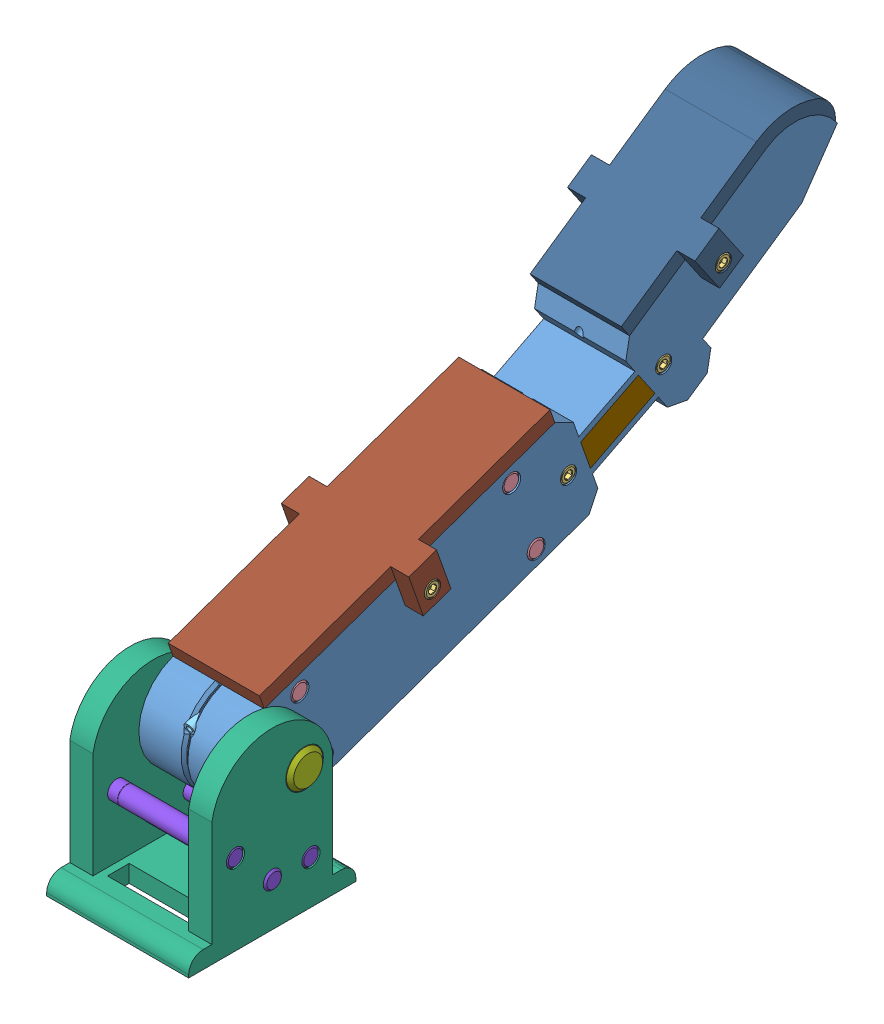
SolidWorks assembly Model B Assembly, configuration Default. Lengths in mm.
Overall size (26.04 78.97 124.79).
25 component instances, 12 part files, 57 mates.
Components (placement in the parent):
- Finger Model B-1: Finger Model B [Default] at (-12.064 21.67 -16.256) x (1 0 0) z (0 -0.332894 0.942964) size (16 27.73 116.61)
- 91253A106-1: 91253A106 [91253A106] at (-12.064 33.526 -38.064) x (1 0.000004 -0.000013) z (0 0.942964 0.332894) size (6.48 6.48 6.63)
- SetScrew-1: SetScrew [90778A103] at (-5.6515 38.9776 -66.5955) x (0 0 -1) z (1 0 0) size (3.29 2.88 3.42)
- Dowel Pins-1: Dowel Pins [97395A445] at (-12.0079 29.664 -19.4945) size (15.88 3.17 3.17)
- Dowel Pins-2: Dowel Pins [97395A445] at (-12.065 42.7701 -56.619) size (15.88 3.17 3.17)
- Dowel Pins-3: Dowel Pins [97395A445] at (-11.938 17.4809 -23.7955) size (15.88 3.17 3.17)
- Dowel Pins-4: Dowel Pins [97395A445] at (-11.938 30.587 -60.92) size (15.88 3.17 3.17)
- 91253A106-2: 91253A106 [91253A106] at (-12.064 60.3378 -94.3511) x (1 -0.000019 0.000027) z (0 0.824674 0.565608) size (6.48 6.48 6.63)
- SetScrew-2: SetScrew [90778A103] at (-5.6515 47.4511 -83.2656) x (0 0 -1) z (1 0 0) size (3.29 2.88 3.42)
- SetScrew-3: SetScrew [90778A103] at (-18.4765 47.4511 -83.2656) x (0 -0.948624 0.316407) z (-1 0 0) size (3.29 2.88 3.42)
- SetScrew-4: SetScrew [90778A103] at (-18.4765 38.9776 -66.5955) x (0 -0.948624 0.316407) z (-1 0 0) size (3.29 2.88 3.42)
- Inlet Tube-1: Inlet Tube [Default] at (-12.064 28.1843 -15.3031) x (1 -0.000168 -0.000059) z (0 -0.332894 0.942964) size (1.8 1.8 7.62)
- New Base Design-2: New Base Design [Default] at (-24.892 21.67 -16.5955) x (0 0 -1) z (1 0 0) size (29.32 30.61 24.89)
- 1-4 inch 1 inch length-1: 1-4 inch 1 inch length [97395A491] at (-12.065 21.67 -16.256) x (1 0 0) z (0 -0.936761 0.34997) size (25.4 6.35 6.35)
- 1-8 inch 1 inch length-1: 1-8 inch 1 inch length [97395A452] at (-12.7 14.1232 -4.1495) x (1 0 0) z (0 0.67783 0.735218) size (25.4 3.17 3.17)
- 1-8 inch 1 inch length-2: 1-8 inch 1 inch length [97395A452] at (-12.7 7.62 -17.382) size (25.4 3.17 3.17)
- Flexure Joint-1: Flexure Joint [Default] at (0 1.8263 0.8872) x (1 0 0) z (0 0.891446 0.453128) size (16 25.4 5.08)
- 2nd Digit Pad^Model B Assembly-1: 2nd Digit Pad^Model B Assembly [Default] at origin (virtual)
- 2nd Digit Pad-1: 2nd Digit Pad [Default] at (-20.066 54.7918 -77.2834) x (0 -0.824674 -0.565608) z (1 0 0) size (11.43 39.04 22.35)
- SetScrew-5: SetScrew [90778A103] at (-2.4765 60.8142 -90.555) x (0 -0.30344 -0.952851) z (1 0 0) size (3.29 2.88 3.42)
- SetScrew-6: SetScrew [90778A103] at (-21.6535 60.8142 -90.555) x (0 -0.948624 0.316407) z (-1 0 0) size (3.29 2.88 3.42)
- 1st Digit Pad-1: 1st Digit Pad [Default] at (-4.064 30.1566 -13.26) x (1 0 0) z (0 0.942964 0.332894) size (22.35 54.01 7.62)
- SetScrew-7: SetScrew [90778A103] at (-2.4765 36.7515 -39.5709) x (0 -0.624397 0.781107) z (1 0 0) size (3.29 2.88 3.42)
- SetScrew-8: SetScrew [90778A103] at (-21.6515 36.7515 -39.5709) x (0 -0.908534 -0.417811) z (-1 0 0) size (3.29 2.88 3.42)
- 1-8 inch 1 inch length-3: 1-8 inch 1 inch length [97395A452] at (-12.3825 7.62 -10.596) size (25.4 3.17 3.17)
Mates (geometry in assembly coordinates):
- Concentric2: concentric anti-aligned: circle of Finger Model B-1; circle of 91253A106-1
- Coincident2: coincident aligned: plane of Finger Model B-1 through (-12.064 25.3664 -14.9511) normal (0 0.942964 0.332894); plane of 91253A106-1 through (-12.064 33.0524 -36.7228) normal (0 0.942964 0.332894)
- Concentric3: concentric anti-aligned: circle of Finger Model B-1; circle of SetScrew-1
- Coincident3: coincident aligned: plane of Finger Model B-1 through (-4.064 21.67 -16.256) normal (1 0 0); plane of SetScrew-1 through (-4.064 38.9776 -66.5955) normal (1 0 0)
- Concentric4: concentric aligned: circle of Finger Model B-1; circle of Dowel Pins-1
- Distance1: distance = 0.0064 mm aligned: plane of Dowel Pins-1 through (-4.0704 29.664 -19.4945) normal (1 0 0); plane of Finger Model B-1 through (-4.064 21.67 -16.256) normal (1 0 0)
- Concentric5: concentric aligned: circle of Finger Model B-1; circle of Dowel Pins-2
- Distance2: distance = 0.0635 mm aligned: plane of Dowel Pins-2 through (-4.1275 42.7701 -56.619) normal (1 0 0); plane of Finger Model B-1 through (-4.064 21.67 -16.256) normal (1 0 0)
- Concentric6: concentric aligned: circle of Finger Model B-1; circle of Dowel Pins-3
- Distance3: distance = 0.0635 mm aligned: plane of Dowel Pins-3 through (-4.0005 17.4809 -23.7955) normal (1 0 0); plane of Finger Model B-1 through (-4.064 21.67 -16.256) normal (1 0 0)
- Concentric7: concentric aligned: circle of Finger Model B-1; circle of Dowel Pins-4
- Distance4: distance = 0.0635 mm aligned: plane of Dowel Pins-4 through (-4.0005 30.587 -60.92) normal (1 0 0); plane of Finger Model B-1 through (-4.064 21.67 -16.256) normal (1 0 0)
- Concentric8: concentric anti-aligned: circle of Finger Model B-1; circle of 91253A106-2
- Coincident8: coincident aligned: plane of Finger Model B-1 through (-12.064 11.5406 -23.2033) normal (0 0.824674 0.565608); plane of 91253A106-2 through (-12.064 59.5333 -93.1781) normal (0 0.824674 0.565608)
- Concentric9: concentric anti-aligned: circle of Finger Model B-1; circle of SetScrew-2
- Coincident9: coincident aligned: plane of Finger Model B-1 through (-4.064 21.67 -16.256) normal (1 0 0); plane of SetScrew-2 through (-4.064 47.4511 -83.2656) normal (1 0 0)
- Concentric10: concentric anti-aligned: circle of Finger Model B-1; circle of SetScrew-3
- Coincident10: coincident aligned: plane of Finger Model B-1 through (-20.064 21.67 -16.256) normal (-1 0 0); plane of SetScrew-3 through (-20.064 47.4511 -83.2656) normal (-1 0 0)
- Concentric11: concentric anti-aligned: circle of Finger Model B-1; circle of SetScrew-4
- Coincident11: coincident aligned: plane of Finger Model B-1 through (-20.064 21.67 -16.256) normal (-1 0 0); plane of SetScrew-4 through (-20.064 38.9776 -66.5955) normal (-1 0 0)
- Coincident12: coincident anti-aligned: circle of Finger Model B-1; circle of Inlet Tube-1
- Coincident13: coincident aligned: plane of Finger Model B-1 through (-5.334 25.7892 -16.1486) normal (0 0.332894 -0.942964); plane of Inlet Tube-1 through (-12.064 28.1843 -15.3031) normal (0 0.332894 -0.942964)
- Concentric17: concentric aligned: circle of Finger Model B-1; circle of New Base Design-2
- Coincident19: coincident anti-aligned: plane of Finger Model B-1 through (-4.064 21.67 -16.256) normal (1 0 0); plane of New Base Design-2 through (-4.064 3.048 -21.844) normal (-1 0 0)
- Concentric21: concentric aligned: circle of New Base Design-2; circle of 1-8 inch 1 inch length-2
- Coincident22: coincident aligned: plane of New Base Design-2 through (0 19.8765 -10.596) normal (1 0 0); plane of 1-8 inch 1 inch length-2 through (0 7.62 -17.382) normal (1 0 0)
- Parallel2: parallel anti-aligned: plane of New Base Design-2 through (0 0 -25.256) normal (0 -1 0); plane of assembly through (0 0 0) normal (0 1 0)
- Coincident24: coincident anti-aligned: plane of New Base Design-2 through (0 0 -25.256) normal (0 -1 0); plane of assembly through (0 0 0) normal (0 1 0)
- Coincident25: coincident aligned: plane of New Base Design-2 through (0 3.048 0) normal (0 0 1); plane of assembly through (0 0 0) normal (0 0 1)
- Coincident26: coincident aligned: plane of New Base Design-2 through (0 19.8765 -10.596) normal (1 0 0); plane of assembly through (0 0 0) normal (1 0 0)
- Concentric22: concentric aligned: circle of New Base Design-2; circle of 1-8 inch 1 inch length-1
- Coincident27: coincident aligned: plane of New Base Design-2 through (0 19.8765 -10.596) normal (1 0 0); plane of 1-8 inch 1 inch length-1 through (0 14.1232 -4.1495) normal (1 0 0)
- Coincident31: coincident anti-aligned: plane of Finger Model B-1 through (-47.2257 35.1954 -64.7601) normal (0 0.891446 0.453128); plane of Flexure Joint-1 through (0 1.8263 0.8872) normal (0 -0.891446 -0.453128)
- Coincident32: coincident aligned: plane of Finger Model B-1 through (-4.064 21.67 -16.256) normal (1 0 0); plane of Flexure Joint-1 through (-4.064 42.6083 -68.1328) normal (1 0 0)
- Coincident33: coincident aligned: plane of Finger Model B-1 through (-20.064 21.67 -16.256) normal (-1 0 0); plane of Flexure Joint-1 through (-20.064 48.3489 -79.4264) normal (-1 0 0)
- Coincident37: coincident anti-aligned: plane of Finger Model B-1 through (-47.2257 39.7239 -62.4582) normal (0 0.453128 -0.891446); plane of Flexure Joint-1 through (-17.524 39.7239 -62.4582) normal (0 -0.453128 0.891446)
- Concentric23: concentric anti-aligned: circle of 2nd Digit Pad-1; circle of SetScrew-5
- Coincident41: coincident aligned: plane of 2nd Digit Pad-1 through (-0.889 54.7918 -77.2834) normal (1 0 0); plane of SetScrew-5 through (-0.889 60.8142 -90.555) normal (1 0 0)
- Concentric24: concentric aligned: circle of 2nd Digit Pad-1; circle of SetScrew-6
- Coincident42: coincident aligned: plane of 2nd Digit Pad-1 through (-23.241 54.7918 -77.2834) normal (-1 0 0); plane of SetScrew-6 through (-23.241 60.8142 -90.555) normal (-1 0 0)
- Parallel3: parallel anti-aligned: plane of Finger Model B-1 through (-4.064 48.9823 -66.5858) normal (0 0.942964 0.332894); plane of 1st Digit Pad-1 through (-4.064 30.1566 -13.26) normal (0 -0.942964 -0.332894)
- Coincident45: coincident anti-aligned: line of Finger Model B-1 through (-4.064 30.1566 -13.26) axis (-1 0 0); line of 1st Digit Pad-1 through (-20.064 30.1566 -13.26) axis (1 0 0)
- Parallel4: parallel aligned: plane of Finger Model B-1 through (-4.064 48.9823 -66.5858) normal (0 0.942964 0.332894); plane of 1st Digit Pad-1 through (-4.064 32.5518 -12.4144) normal (0 0.942964 0.332894)
- Coincident47: coincident aligned: plane of Finger Model B-1 through (-4.064 21.67 -16.256) normal (1 0 0); plane of 1st Digit Pad-1 through (-4.064 50.5318 -63.3451) normal (1 0 0)
- Concentric25: concentric anti-aligned: circle of 1st Digit Pad-1; circle of SetScrew-7
- Coincident48: coincident aligned: plane of 1st Digit Pad-1 through (-0.889 30.1566 -13.26) normal (1 0 0); plane of SetScrew-7 through (-0.889 36.7515 -39.5709) normal (1 0 0)
- Concentric26: concentric aligned: circle of 1st Digit Pad-1; circle of SetScrew-8
- Coincident49: coincident aligned: plane of 1st Digit Pad-1 through (-23.239 30.1566 -13.26) normal (-1 0 0); plane of SetScrew-8 through (-23.239 36.7515 -39.5709) normal (-1 0 0)
- Coincident50: coincident anti-aligned: circle of New Base Design-2; circle of 1-8 inch 1 inch length-3
- Parallel5: parallel aligned: plane of New Base Design-2 through (0 19.8765 -10.596) normal (1 0 0); plane of 1-8 inch 1 inch length-3 through (0.3175 7.62 -10.596) normal (1 0 0)
- Concentric27: concentric anti-aligned: cylinder of New Base Design-2 through (0 21.67 -16.256) axis (-1 0 0) radius 3.302; cylinder of 1-4 inch 1 inch length-1 through (-24.765 21.67 -16.256) axis (1 0 0) radius 3.175
- Coincident51: coincident anti-aligned: plane of New Base Design-2 through (0 19.8765 -10.596) normal (1 0 0); circle of 1-4 inch 1 inch length-1
- Coincident53: coincident aligned: plane of Finger Model B-1 through (-4.064 21.67 -16.256) normal (1 0 0); plane of 2nd Digit Pad-1 through (-4.064 63.6946 -105.9815) normal (1 0 0)
- Coincident54: coincident aligned: line of Finger Model B-1 through (-20.064 54.7918 -77.2834) axis (1 0 0); line of 2nd Digit Pad-1 through (-20.066 54.7918 -77.2834) axis (1 0 0)
- Coincident55: coincident aligned: plane of Finger Model B-1 through (-4.064 21.67 -16.256) normal (1 0 0); plane of 2nd Digit Pad-1 through (-4.064 63.6946 -105.9815) normal (1 0 0)
- Coincident56: coincident: plane of Finger Model B-1 through (-4.064 21.67 -16.256) normal (1 0 0); line of 2nd Digit Pad-1 through (-4.064 71.0259 -100.9532) axis (0 -0.565608 0.824674)
- Coincident57: coincident: line of Finger Model B-1 through (-4.064 71.1962 -101.2016) axis (0 -0.565608 0.824674); plane of 2nd Digit Pad-1 through (-20.066 71.0259 -100.9532) normal (0 -0.824674 -0.565608)
